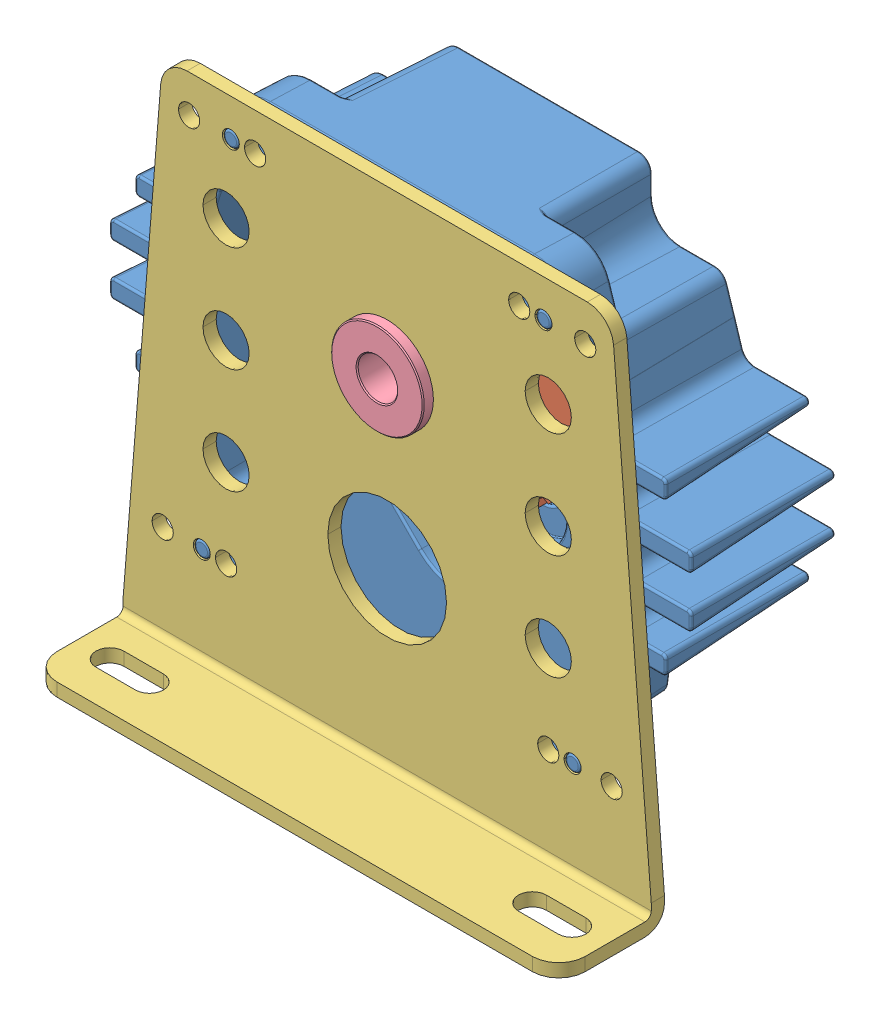
SolidWorks assembly TBM, configuration Default. Lengths in mm.
Overall size (139.9 123.97 63.76).
5 component instances, 4 part files, 8 mates.
Components (placement in the parent):
- am-0650 - Toughbox Mini Housing-1: am-0650 - Toughbox Mini Housing [Default] at (60.1528 67.2785 74.9723) size (139.9 118.54 41.53)
- am-0149 - 50T Toughbox Large Cluster Gear - steel-1: am-0149 - 50T Toughbox Large Cluster Gear - steel [Default] at (60.1528 107.9947 97.4206) x (0 0 -1) z (0.997948 -0.064032 0) size (10.16 65.97 66.04)
- am-0647 TM Shaft Plate-1: am-0647 TM Shaft Plate [Default] at (60.1528 86.5317 113.9613) x (-1 0 0) z (0 0 -1) size (127 123.82 25.4)
- FR6ZZ Bearing_smart-1: FR6ZZ Bearing_smart [Default] at (60.1528 107.9947 109.2663) x (0 0 1) z (-1 0 0) size (7.16 24.69 24.69)
- FR6ZZ Bearing_smart-2: FR6ZZ Bearing_smart [Default] at (60.1528 107.9947 83.6043) x (0 0 -1) z (1 0 0) size (7.16 24.69 24.69)
Mates (geometry in assembly coordinates):
- Concentric1: concentric anti-aligned: cylinder of am-0650 - Toughbox Mini Housing-1 through (60.1528 107.9947 76.4963) axis (0 0 1) radius 11.1061; cylinder of am-0149 - 50T Toughbox Large Cluster Gear - steel-1 through (60.1528 107.9947 87.2606) axis (0 0 -1) radius 6.985
- Concentric3: concentric anti-aligned: cone of am-0650 - Toughbox Mini Housing-1 through (97.7448 137.8664 110.7863) axis (0 0 1); cylinder of am-0647 TM Shaft Plate-1 through (97.7448 137.8664 110.7863) axis (0 0 -1) radius 2.0447
- Concentric4: concentric anti-aligned: cone of am-0650 - Toughbox Mini Housing-1 through (22.5608 137.8664 110.7863) axis (0 0 1); cylinder of am-0647 TM Shaft Plate-1 through (22.5608 137.8664 110.7863) axis (0 0 -1) radius 2.0447
- Coincident2: coincident anti-aligned: plane of am-0650 - Toughbox Mini Housing-1 through (60.1528 67.2785 110.7863) normal (0 0 1); plane of am-0647 TM Shaft Plate-1 through (6.1778 146.8567 110.7863) normal (0 0 -1)
- Concentric5: concentric anti-aligned: cylinder of am-0647 TM Shaft Plate-1 through (60.1528 107.9947 110.7863) axis (0 0 -1) radius 11.1061; cylinder of FR6ZZ Bearing_smart-1 through (60.1528 107.9947 116.4263) axis (0 0 1) radius 11.115
- Coincident4: coincident anti-aligned: plane of am-0647 TM Shaft Plate-1 through (6.1778 146.8567 110.7863) normal (0 0 -1); plane of FR6ZZ Bearing_smart-1 through (60.1528 107.9947 110.7863) normal (0 0 1)
- Concentric6: concentric anti-aligned: cylinder of am-0650 - Toughbox Mini Housing-1 through (60.1528 107.9947 76.4963) axis (0 0 1) radius 11.1061; cylinder of FR6ZZ Bearing_smart-2 through (60.1528 107.9947 76.4443) axis (0 0 -1) radius 11.115
- Coincident5: coincident anti-aligned: plane of am-0650 - Toughbox Mini Housing-1 through (91.9028 137.8664 82.0843) normal (0 0 1); plane of FR6ZZ Bearing_smart-2 through (60.1528 107.9947 82.0843) normal (0 0 -1)
